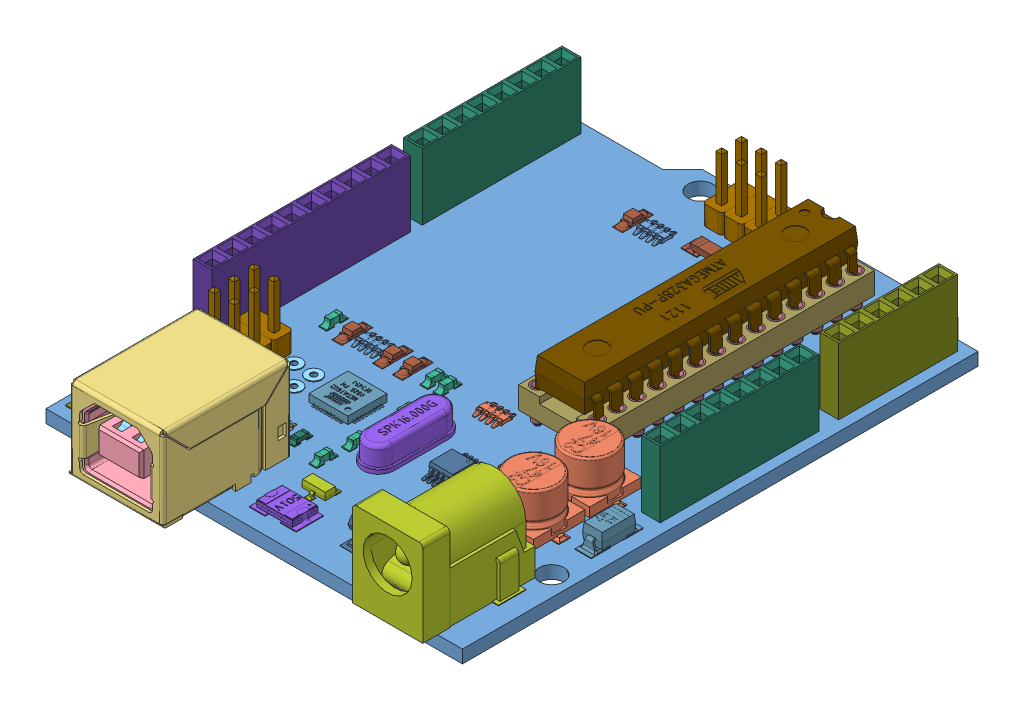
SolidWorks assembly arduino uno, configuration Default. Lengths in mm.
Overall size (53.34 15.25 74.97).
88 component instances, 35 part files, 136 mates.
Components (placement in the parent):
- unoboard blue-1: unoboard blue [Default] at origin size (53.34 1.65 68.58)
- 47uf CAP Dcase-1: 47uf CAP Dcase [Default] at (-9.4141 0 -18.4991) x (0 0 -1) z (1 0 0) size (6.6 5.81 8)
- USB type b-1: USB type b [Default] at (-38.02 0.43 6.35) size (14.34 15.2 16.54)
  - USB SHELL-1: USB SHELL [Default] at origin size (14.34 15.2 16.54)
  - USB core-1: USB core [Default] at origin size (11.3 10.68 15.75)
  - usb top contact-1: usb top contact [Default] at (1.25 6.09 -0.38) size (1 9.67 13.76)
  - usb btm contact-1: usb btm contact [Default] at (1.25 4.41 -0.38) size (1 6.84 11.76)
  - usb btm contact-2: usb btm contact [Default] at (-1.25 4.41 -0.38) size (1 6.84 11.76)
  - usb top contact-2: usb top contact [Default] at (-1.25 6.09 -0.38) size (1 9.67 13.76)
- power jack-1: power jack [Default] at (-7.675 0 1.905) size (11.2 15.2 15.9)
- 47uf CAP Dcase-2: 47uf CAP Dcase [Default] at (-9.4141 0 -25.7132) x (0 0 -1) z (1 0 0) size (6.6 5.81 8)
- crystal-1: crystal [Default] at (-26.162 0 -18.923) x (1 0 0) z (0 0 -1) size (4 5 11)
- 2pin_header__02-1: 2pin_header__02 [Default] at (-46.23 0 -15.75) size (5 11.75 2.54)
- nano - reg-1: nano - reg [Default] at (-17.399 0 -7.747) size (6.5 1.69 8.3)
- led-1: led [Default] at (-34.29 0 -27.94) x (0 0 1) z (-1 0 0) size (4 0.86 1.35)
- 2pin_header__02-2: 2pin_header__02 [Default] at (-30.43 0 -64.91) x (0 0 1) z (-1 0 0) size (5 11.75 2.54)
- dip28-1: dip28 [Default] at (-16.383 1.5 -46.355) x (0 0 -1) z (1 0 0) size (35.48 7.37 10.1)
  - dip28-1: dip28 [Default] at origin size (35.48 2.8 10.1)
  - dip socket pin-1: dip socket pin [Default] at (16.51 2.8 -3.81) size (1.7 7.37 1.7)
  - dip socket pin-2: dip socket pin [Default] at (16.51 2.8 3.81) size (1.7 7.37 1.7)
  - dip socket pin-3: dip socket pin [Default] at (13.97 2.8 -3.81) size (1.7 7.37 1.7)
  - dip socket pin-4: dip socket pin [Default] at (13.97 2.8 3.81) size (1.7 7.37 1.7)
  - dip socket pin-5: dip socket pin [Default] at (11.43 2.8 -3.81) size (1.7 7.37 1.7)
  - dip socket pin-6: dip socket pin [Default] at (11.43 2.8 3.81) size (1.7 7.37 1.7)
  - dip socket pin-7: dip socket pin [Default] at (8.89 2.8 -3.81) size (1.7 7.37 1.7)
  - dip socket pin-8: dip socket pin [Default] at (8.89 2.8 3.81) size (1.7 7.37 1.7)
  - dip socket pin-9: dip socket pin [Default] at (6.35 2.8 -3.81) size (1.7 7.37 1.7)
  - dip socket pin-10: dip socket pin [Default] at (6.35 2.8 3.81) size (1.7 7.37 1.7)
  - dip socket pin-11: dip socket pin [Default] at (3.81 2.8 -3.81) size (1.7 7.37 1.7)
  - dip socket pin-12: dip socket pin [Default] at (3.81 2.8 3.81) size (1.7 7.37 1.7)
  - dip socket pin-13: dip socket pin [Default] at (1.27 2.8 -3.81) size (1.7 7.37 1.7)
  - dip socket pin-14: dip socket pin [Default] at (1.27 2.8 3.81) size (1.7 7.37 1.7)
  - dip socket pin-15: dip socket pin [Default] at (-1.27 2.8 -3.81) size (1.7 7.37 1.7)
  - dip socket pin-16: dip socket pin [Default] at (-1.27 2.8 3.81) size (1.7 7.37 1.7)
  - dip socket pin-17: dip socket pin [Default] at (-3.81 2.8 -3.81) size (1.7 7.37 1.7)
  - dip socket pin-18: dip socket pin [Default] at (-3.81 2.8 3.81) size (1.7 7.37 1.7)
  - dip socket pin-19: dip socket pin [Default] at (-6.35 2.8 -3.81) size (1.7 7.37 1.7)
  - dip socket pin-20: dip socket pin [Default] at (-6.35 2.8 3.81) size (1.7 7.37 1.7)
  - dip socket pin-21: dip socket pin [Default] at (-8.89 2.8 -3.81) size (1.7 7.37 1.7)
  - dip socket pin-22: dip socket pin [Default] at (-8.89 2.8 3.81) size (1.7 7.37 1.7)
  - dip socket pin-23: dip socket pin [Default] at (-11.43 2.8 -3.81) size (1.7 7.37 1.7)
  - dip socket pin-24: dip socket pin [Default] at (-11.43 2.8 3.81) size (1.7 7.37 1.7)
  - dip socket pin-25: dip socket pin [Default] at (-13.97 2.8 -3.81) size (1.7 7.37 1.7)
  - dip socket pin-26: dip socket pin [Default] at (-13.97 2.8 3.81) size (1.7 7.37 1.7)
  - dip socket pin-27: dip socket pin [Default] at (-16.51 2.8 -3.81) size (1.7 7.37 1.7)
  - dip socket pin-28: dip socket pin [Default] at (-16.51 2.8 3.81) size (1.7 7.37 1.7)
- 2pin_header__02-3: 2pin_header__02 [Default] at (-27.89 0 -64.91) x (0 0 1) z (-1 0 0) size (5 11.75 2.54)
- 2pin_header__02-4: 2pin_header__02 [Default] at (-25.35 0 -64.91) x (0 0 1) z (-1 0 0) size (5 11.75 2.54)
- 2pin_header__02-5: 2pin_header__02 [Default] at (-46.23 0 -18.29) size (5 11.75 2.54)
- 2pin_header__02-6: 2pin_header__02 [Default] at (-46.23 0 -20.83) size (5 11.75 2.54)
- atmega16u2-1: atmega16u2 [Default] at (-34.671 0.06 -20) x (1 0 0) z (0 0 -1) size (5.5 1.01 5.5)
- led-2: led [Default] at (-36.83 0 -27.94) x (0 0 1) z (-1 0 0) size (4 0.86 1.35)
- led-3: led [Default] at (-42.037 0 -27.94) x (0 0 1) z (-1 0 0) size (4 0.86 1.35)
- led-4: led [Default] at (-36.576 0 -58.42) x (0 0 1) z (-1 0 0) size (4 0.86 1.35)
- 8 PORT HEADER-3: 8 PORT HEADER [Default] at (-50.8 0 -45.72) x (0 0 -1) z (1 0 0) size (20.32 10.51 2.41)
- 8 PORT HEADER-4: 8 PORT HEADER [Default] at (-2.54 0 -27.94) x (0 0 -1) z (1 0 0) size (20.32 10.51 2.41)
- 6 PORT HEADER-3: 6 PORT HEADER [Default] at (-2.54 0 -50.8) x (0 0 -1) z (1 0 0) size (15.24 10.51 2.41)
- 10 PORT HEADER-1: 10 PORT HEADER [Default] at (-50.8 0 -18.796) x (0 0 -1) z (1 0 0) size (25.4 10.51 2.41)
- ATMEL328P-1: ATMEL328P [Default] at (-16.383 4.3 -46.355) x (0 0 -1) z (1 0 0) size (35 7.27 7.87)
- 102 RESISTOR PACK-1: 102 RESISTOR PACK [Default] at (-33.782 0 -58.42) size (3.2 0.46 3)
- 102 RESISTOR PACK-2: 102 RESISTOR PACK [Default] at (-39.37 0 -27.94) size (3.2 0.46 3)
- 103 RESISTOR PACK-3: 103 RESISTOR PACK [Default] at (-23.876 0 -27.94) size (3.2 0.46 3)
- 220 RESISTOR PACK-1: 220 RESISTOR PACK [Default] at (-36.83 0 -12.827) size (3.2 0.46 3)
- 16mhz crystal - measured-1: 16mhz crystal - measured [Default] at (-24.892 0 -41.275) x (0 0 -1) z (1 0 0) size (3.4 0.8 2)
- PADS001-1: PADS001 [Default] at (-39.878 0.1 -18.288) x (-1 0 0) z (0 0 1) size (4.54 0.1 4.54)
- 603 cap on pad-1: 603 cap on pad [Default] at (-44.45 0 -27.94) x (0 0 -1) z (1 0 0) size (2.76 0.9 1.12)
- ssot3-1: ssot3 [Default] at (-26.5 0 -8.128) x (-1 0 0) z (0 0 -1) size (3 1.13 3.09)
- mf-msmf050-2-1: mf-msmf050-2 [Default] at (-26.5 0 -4.064) size (5.77 1.02 3.72)
- 603 cap on pad-2: 603 cap on pad [Default] at (-29.845 0 -27.94) x (0 0 -1) z (1 0 0) size (2.76 0.9 1.12)
- 603 cap on pad-3: 603 cap on pad [Default] at (-31.496 0 -27.94) x (0 0 -1) z (1 0 0) size (2.76 0.9 1.12)
- lmv358-1: lmv358 [Default] at (-15.24 0 -21.971) x (0 0 -1) z (1 0 0) size (3.7 1.4 2.9)
- 603 cap on pad-4: 603 cap on pad [Default] at (-15.24 0 -18.415) size (2.76 0.9 1.12)
- 603 cap on pad-5: 603 cap on pad [Default] at (-29.845 0 -12.065) x (0 0 1) z (-1 0 0) size (2.76 0.9 1.12)
- 603 cap on pad-6: 603 cap on pad [Default] at (-29.591 0 -22.352) x (0 0 1) z (-1 0 0) size (2.76 0.9 1.12)
- 603 cap on pad-7: 603 cap on pad [Default] at (-29.591 0 -16.002) x (0 0 1) z (-1 0 0) size (2.76 0.9 1.12)
- 603 cap on pad-8: 603 cap on pad [Default] at (-41.91 0 -12.7) x (0 0 1) z (-1 0 0) size (2.76 0.9 1.12)
- lp2985dgkr-1: lp2985dgkr [Default] at (-20.32 0 -19.05) x (0 0 -1) z (1 0 0) size (5.85 1.1 3)
- cd1206 diode-1: cd1206 diode [Default] at (-27.94 0 -59.436) x (0 0 -1) z (1 0 0) size (2.07 0.96 5)
- cd1206 diode-2: cd1206 diode [Default] at (-46.228 0 -13.081) x (0 0 1) z (-1 0 0) size (2.07 0.96 5)
- 603 resistor-1: 603 resistor [Default] at (-29.591 0 -19.05) x (0 0 1) z (-1 0 0) size (2.36 0.61 1.03)
- blm21-1: blm21 [Default] at (-45.085 0 -7.62) x (0 0 -1) z (1 0 0) size (2.76 0.95 1.32)
- m7 diode-1: m7 diode [Default] at (-2.794 0 -21.59) x (0 0 -1) z (1 0 0) size (6.66 2.35 2.5)
- MLC0603-1: MLC0603 [Default] at (-33.655 0 -12.827) x (0 0 -1) z (1 0 0) size (2.36 0.6 1.03)
- MLC0603-2: MLC0603 [Default] at (-39.37 0 -12.827) x (0 0 -1) z (1 0 0) size (2.36 0.6 1.03)
- RESET BUTTON-1: RESET BUTTON [Default] at (-49.403 0 -6.35) size (6.2 3.1 9.6)
  - RESET CORE-1: RESET CORE [Default] at (0 0.1 0) x (-1 0 0) z (0 0 -1) size (6.2 3.1 9.6)
  - RESET-1: RESET [Default] at (0 0.1 0) x (0 0 1) z (-1 0 0) size (7.3 2 6.2)
- 603 cap on pad-9: 603 cap on pad [Default] at (-15.24 0 -25.625) size (2.76 0.9 1.12)
Mates (geometry in assembly coordinates):
- Distance1: distance = 1.905 mm aligned: plane of power jack-1 through (-7.675 0 1.905) normal (0 0 1); plane of unoboard blue-1 through (0 0 0) normal (0 0 1)
- Coincident2: coincident aligned: plane of unoboard blue-1 through (0 0 0) normal (0 1 0); plane of power jack-1 through (-7.675 0 1.905) normal (0 1 0)
- Coincident3: coincident anti-aligned: plane of unoboard blue-1 through (0 0 0) normal (0 1 0); plane of USB type b-1/USB core-1 through (-38.02 0 6.35) normal (0 -1 0)
- Distance2: distance = 6.35 mm aligned: plane of USB type b-1/USB SHELL-1 through (-38.02 0.43 6.35) normal (0 0 1); plane of unoboard blue-1 through (0 0 0) normal (0 0 1)
- Coincident5: coincident aligned: plane of unoboard blue-1 through (0 0 0) normal (0 1 0); plane of 47uf CAP Dcase-1
- Parallel1: parallel anti-aligned: plane of unoboard blue-1 through (0 0 0) normal (0 0 1); plane of 47uf CAP Dcase-1 through (-9.4141 0 -18.4991) normal (0 0 -1)
- Coincident7: coincident aligned: plane of 47uf CAP Dcase-1 through (-6.1141 1.5 -15.1991) normal (1 0 0); plane of 47uf CAP Dcase-2 through (-6.1141 1.5 -22.4132) normal (1 0 0)
- Coincident8: coincident anti-aligned: plane of unoboard blue-1 through (0 0 0) normal (0 1 0); plane of 47uf CAP Dcase-2 through (-8.1891 0 -25.7132) normal (0 -1 0)
- Distance3: distance = 3.175 mm aligned: plane of power jack-1 through (-3.175 10.5 -1.595) normal (1 0 0); plane of unoboard blue-1 through (0 -1.65 0) normal (1 0 0)
- Distance4: distance = 32 mm aligned: plane of USB type b-1/USB SHELL-1 through (-32 0.43 6.35) normal (1 0 0); plane of unoboard blue-1 through (0 -1.65 0) normal (1 0 0)
- Coincident11: coincident anti-aligned: plane of unoboard blue-1 through (0 0 0) normal (0 1 0); plane of crystal-1 through (-26.162 0 -22.423) normal (0 -1 0)
- Concentric1: concentric aligned: cylinder of unoboard blue-1 through (-26.162 -10 -16.383) axis (0 1 0) radius 0.5; cylinder of crystal-1 through (-26.162 -2 -16.383) axis (0 1 0) radius 0.4
- Concentric2: concentric aligned: cylinder of unoboard blue-1 through (-26.162 -10 -21.463) axis (0 1 0) radius 0.5; cylinder of crystal-1 through (-26.162 -2 -21.463) axis (0 1 0) radius 0.4
- Coincident12: coincident anti-aligned: plane of unoboard blue-1 through (0 0 0) normal (0 1 0); plane of 2pin_header__02-1 through (-44.23 0 -14.98) normal (0 -1 0)
- Distance5: distance = 15.75 mm aligned: plane of 2pin_header__02-1 through (-46.23 0 -15.75) normal (0 0 1); plane of assembly through (0 0 0) normal (0 0 1)
- Distance6: distance = 46.23 mm aligned: plane of 2pin_header__02-1 through (-46.23 0 -15.75) normal (1 0 0); plane of assembly through (0 0 0) normal (1 0 0)
- Coincident15: coincident anti-aligned: plane of unoboard blue-1 through (0 0 0) normal (0 1 0); plane of 2pin_header__02-2 through (-31.2 0 -62.91) normal (0 -1 0)
- Distance7: distance = 64.91 mm aligned: plane of 2pin_header__02-2 through (-30.43 0 -64.91) normal (0 0 1); plane of assembly through (0 0 0) normal (0 0 1)
- Distance8: distance = 30.43 mm anti-aligned: plane of 2pin_header__02-2 through (-30.43 0 -64.91) normal (-1 0 0); plane of assembly through (0 0 0) normal (1 0 0)
- Coincident19: coincident anti-aligned: plane of unoboard blue-1 through (0 0 0) normal (0 1 0); plane of nano - reg-1 through (-17.399 0 -7.747) normal (0 -1 0)
- Concentric3: concentric aligned: cylinder of unoboard blue-1 through (-20.193 -10 -62.865) axis (0 1 0) radius 0.4; cylinder of dip28-1/dip socket pin-1 through (-20.193 33.2926 -62.865) axis (0 1 0) radius 0.25
- Concentric4: concentric aligned: cylinder of unoboard blue-1 through (-12.573 -10 -29.845) axis (0 1 0) radius 0.4; cylinder of dip28-1/dip socket pin-28 through (-12.573 33.2926 -29.845) axis (0 1 0) radius 0.25
- Distance9: distance = 1.5 mm anti-aligned: plane of dip28-1/dip28-1 through (-11.333 1.5 -64.095) normal (0 -1 0); plane of unoboard blue-1 through (0 0 0) normal (0 1 0)
- Coincident21: coincident anti-aligned: plane of unoboard blue-1 through (0 0 0) normal (0 1 0); plane of atmega16u2-1 through (-34.671 0 -20) normal (0 -1 0)
- Distance10: distance = 20 mm anti-aligned: plane of atmega16u2-1 through (-34.671 0.06 -20) normal (0 0 -1); plane of unoboard blue-1 through (0 0 0) normal (0 0 1)
- Distance11: distance = 34.671 mm aligned: plane of atmega16u2-1; plane of unoboard blue-1 through (0 0 0) normal (1 0 0)
- Coincident25: coincident anti-aligned: plane of unoboard blue-1 through (0 0 0) normal (0 1 0); plane of led-1 through (-34.29 0 -28.94) normal (0 -1 0)
- Distance12: distance = 34.29 mm anti-aligned: plane of led-1 through (-34.29 0 -27.94) normal (-1 0 0); plane of unoboard blue-1 through (0 0 0) normal (1 0 0)
- Distance13: distance = 27.94 mm aligned: plane of led-1 through (-34.29 0 -27.94) normal (0 0 1); plane of unoboard blue-1 through (0 0 0) normal (0 0 1)
- Coincident28: coincident aligned: plane of led-2 through (-36.83 0 -28.94) normal (0 -1 0); plane of led-3 through (-42.037 0 -28.94) normal (0 -1 0)
- Coincident29: coincident aligned: plane of led-1 through (-34.29 0 -27.94) normal (0 0 1); plane of led-2 through (-36.83 0 -27.94) normal (0 0 1)
- Coincident30: coincident aligned: plane of led-1 through (-34.29 0 -27.94) normal (0 0 1); plane of led-3 through (-42.037 0 -27.94) normal (0 0 1)
- Distance14: distance = 2.54 mm aligned: plane of led-2 through (-36.83 0 -27.94) normal (-1 0 0); plane of led-1 through (-34.29 0 -27.94) normal (-1 0 0)
- Coincident32: coincident anti-aligned: plane of unoboard blue-1 through (0 0 0) normal (0 1 0); plane of led-2 through (-36.83 0 -28.94) normal (0 -1 0)
- Distance15: distance = 42.037 mm anti-aligned: plane of led-3 through (-42.037 0 -27.94) normal (-1 0 0); plane of unoboard blue-1 through (0 0 0) normal (1 0 0)
- Coincident34: coincident anti-aligned: plane of unoboard blue-1 through (0 0 0) normal (0 1 0); plane of led-4 through (-36.576 0 -59.42) normal (0 -1 0)
- Distance16: distance = 36.576 mm anti-aligned: plane of led-4 through (-36.576 0 -58.42) normal (-1 0 0); plane of unoboard blue-1 through (0 0 0) normal (1 0 0)
- Distance17: distance = 58.42 mm aligned: plane of led-4 through (-36.576 0 -58.42) normal (0 0 1); plane of unoboard blue-1 through (0 0 0) normal (0 0 1)
- Coincident37: coincident aligned: plane of unoboard blue-1 through (0 0 0) normal (0 1 0); plane of 8 PORT HEADER-4
- Coincident38: coincident aligned: plane of unoboard blue-1 through (0 0 0) normal (0 1 0); plane of 8 PORT HEADER-3
- Parallel2: parallel aligned: plane of unoboard blue-1 through (0 0 0) normal (1 0 0); plane of 8 PORT HEADER-4 through (-2.54 0 -27.94) normal (1 0 0)
- Parallel3: parallel aligned: plane of unoboard blue-1 through (0 0 0) normal (1 0 0); plane of 8 PORT HEADER-3 through (-50.8 0 -45.72) normal (1 0 0)
- Concentric5: concentric aligned: cylinder of unoboard blue-1 through (-2.54 -1.65 -27.94) axis (0 1 0) radius 0.4; line of 8 PORT HEADER-4 through (-2.54 -2.5255 -27.94) axis (0 1 0)
- Concentric6: concentric aligned: cylinder of unoboard blue-1 through (-50.8 -1.65 -45.72) axis (0 1 0) radius 0.4; line of 8 PORT HEADER-3 through (-50.8 -2.5255 -45.72) axis (0 1 0)
- Coincident43: coincident aligned: plane of unoboard blue-1 through (0 0 0) normal (0 1 0); plane of 10 PORT HEADER-1
- Coincident44: coincident aligned: plane of unoboard blue-1 through (0 0 0) normal (0 1 0); plane of 6 PORT HEADER-3
- Parallel4: parallel aligned: plane of unoboard blue-1 through (0 0 0) normal (1 0 0); plane of 6 PORT HEADER-3 through (-2.54 0 -50.8) normal (1 0 0)
- Parallel5: parallel aligned: plane of unoboard blue-1 through (0 0 0) normal (1 0 0); plane of 10 PORT HEADER-1 through (-50.8 0 -18.796) normal (1 0 0)
- Concentric7: concentric aligned: cylinder of unoboard blue-1 through (-50.8 -1.65 -18.796) axis (0 1 0) radius 0.4; line of 10 PORT HEADER-1 through (-50.8 -2.5255 -18.796) axis (0 1 0)
- Concentric9: concentric aligned: cylinder of unoboard blue-1 through (-2.54 -1.65 -50.8) axis (0 1 0) radius 0.4; line of 6 PORT HEADER-3 through (-2.54 -2.5255 -50.8) axis (0 1 0)
- Coincident50: coincident aligned: plane of dip28-1/dip28-1 through (-16.383 1.5 -46.355) normal (0 0 -1); plane of ATMEL328P-1 through (-16.383 4.3 -46.355) normal (0 0 -1)
- Coincident51: coincident aligned: plane of dip28-1/dip28-1 through (-16.383 1.5 -46.355) normal (1 0 0); plane of ATMEL328P-1 through (-16.383 4.3 -46.355) normal (1 0 0)
- Coincident52: coincident aligned: plane of dip28-1/dip28-1 through (-11.333 4.3 -64.095) normal (0 1 0); plane of ATMEL328P-1
- Distance18: distance = 7.747 mm: plane of nano - reg-1 through (-17.399 0 -7.747) normal (0 0 1); line of unoboard blue-1 through (-53.34 0 0) axis (1 0 0)
- Distance19: distance = 17.399 mm aligned: plane of nano - reg-1 through (-17.399 0 -7.747) normal (1 0 0); plane of unoboard blue-1 through (0 0 0) normal (1 0 0)
- Coincident55: coincident anti-aligned: plane of unoboard blue-1 through (0 0 0) normal (0 1 0); plane of 102 RESISTOR PACK-1 through (-33.982 0 -59.12) normal (0 -1 0)
- Distance20: distance = 33.782 mm aligned: plane of 102 RESISTOR PACK-1 through (-33.782 0 -58.42) normal (1 0 0); plane of unoboard blue-1 through (0 0 0) normal (1 0 0)
- Distance21: distance = 58.42 mm aligned: plane of 102 RESISTOR PACK-1 through (-33.782 0 -58.42) normal (0 0 1); plane of unoboard blue-1 through (0 0 0) normal (0 0 1)
- Coincident58: coincident aligned: plane of 102 RESISTOR PACK-2 through (-39.37 0 -27.94) normal (0 1 0); plane of 103 RESISTOR PACK-3 through (-23.876 0 -27.94) normal (0 1 0)
- Coincident59: coincident aligned: plane of unoboard blue-1 through (0 0 0) normal (0 1 0); plane of 103 RESISTOR PACK-3 through (-23.876 0 -27.94) normal (0 1 0)
- Coincident60: coincident aligned: plane of 102 RESISTOR PACK-2 through (-39.37 0 -27.94) normal (0 0 1); plane of 103 RESISTOR PACK-3 through (-23.876 0 -27.94) normal (0 0 1)
- Distance22: distance = 23.876 mm aligned: plane of 103 RESISTOR PACK-3 through (-23.876 0 -27.94) normal (1 0 0); plane of unoboard blue-1 through (0 0 0) normal (1 0 0)
- Distance23: distance = 39.37 mm aligned: plane of 102 RESISTOR PACK-2 through (-39.37 0 -27.94) normal (1 0 0); plane of unoboard blue-1 through (0 0 0) normal (1 0 0)
- Distance24: distance = 27.94 mm aligned: plane of 102 RESISTOR PACK-2 through (-39.37 0 -27.94) normal (0 0 1); plane of unoboard blue-1 through (0 0 0) normal (0 0 1)
- Distance25: distance = 12.827 mm aligned: plane of 220 RESISTOR PACK-1 through (-36.83 0 -12.827) normal (0 0 1); plane of unoboard blue-1 through (0 0 0) normal (0 0 1)
- Distance26: distance = 36.83 mm aligned: plane of 220 RESISTOR PACK-1 through (-36.83 0 -12.827) normal (1 0 0); plane of unoboard blue-1 through (0 0 0) normal (1 0 0)
- Coincident66: coincident aligned: plane of unoboard blue-1 through (0 0 0) normal (0 1 0); plane of 220 RESISTOR PACK-1 through (-36.83 0 -12.827) normal (0 1 0)
- Coincident67: coincident anti-aligned: plane of unoboard blue-1 through (0 0 0) normal (0 1 0); plane of 16mhz crystal - measured-1 through (-24.892 0 -41.275) normal (0 -1 0)
- Distance27: distance = 41.275 mm anti-aligned: plane of 16mhz crystal - measured-1 through (-24.892 0 -41.275) normal (0 0 -1); plane of unoboard blue-1 through (0 0 0) normal (0 0 1)
- Distance28: distance = 24.892 mm aligned: plane of 16mhz crystal - measured-1 through (-24.892 0 -41.275) normal (1 0 0); plane of unoboard blue-1 through (0 0 0) normal (1 0 0)
- Coincident70: coincident anti-aligned: plane of unoboard blue-1 through (0 0 0) normal (0 1 0); plane of PADS001-1 through (-42.418 0 -18.288) normal (0 -1 0)
- Distance29: distance = 18.288 mm aligned: plane of PADS001-1 through (-39.878 0.1 -18.288) normal (0 0 1); plane of unoboard blue-1 through (0 0 0) normal (0 0 1)
- Distance30: distance = 39.878 mm anti-aligned: plane of PADS001-1; plane of unoboard blue-1 through (0 0 0) normal (1 0 0)
- Distance31: distance = 4.064 mm aligned: plane of mf-msmf050-2-1 through (-26.5 0 -4.064) normal (0 0 1); plane of unoboard blue-1 through (0 0 0) normal (0 0 1)
- Distance32: distance = 26.5 mm aligned: plane of mf-msmf050-2-1 through (-26.5 0 -4.064) normal (1 0 0); plane of unoboard blue-1 through (0 0 0) normal (1 0 0)
- Coincident72: coincident aligned: plane of unoboard blue-1 through (0 0 0) normal (0 1 0); plane of mf-msmf050-2-1 through (-26.5 0 -4.064) normal (0 1 0)
- Distance33: distance = 8.128 mm anti-aligned: plane of unoboard blue-1 through (0 0 0) normal (0 0 1); plane of ssot3-1 through (-26.5 0 -8.128) normal (0 0 -1)
- Coincident74: coincident anti-aligned: plane of ssot3-1 through (-26.5 0 -8.128) normal (-1 0 0); plane of mf-msmf050-2-1 through (-26.5 0 -4.064) normal (1 0 0)
- Coincident75: coincident aligned: plane of unoboard blue-1 through (0 0 0) normal (0 1 0); plane of ssot3-1
- Coincident76: coincident anti-aligned: plane of led-1 through (-34.29 0 -27.94) normal (0 0 1); plane of 603 cap on pad-1 through (-44.45 0 -27.94) normal (0 0 -1)
- Coincident77: coincident aligned: plane of unoboard blue-1 through (0 0 0) normal (0 1 0); plane of 603 cap on pad-1
- Distance34: distance = 44.45 mm aligned: plane of 603 cap on pad-1 through (-44.45 0 -27.94) normal (1 0 0); plane of unoboard blue-1 through (0 0 0) normal (1 0 0)
- Coincident79: coincident aligned: plane of 603 cap on pad-2; plane of 603 cap on pad-3
- Coincident80: coincident aligned: plane of 603 cap on pad-2 through (-29.845 0 -27.94) normal (0 0 -1); plane of 603 cap on pad-3 through (-31.496 0 -27.94) normal (0 0 -1)
- Coincident81: coincident aligned: plane of unoboard blue-1 through (0 0 0) normal (0 1 0); plane of 603 cap on pad-2
- Coincident82: coincident aligned: plane of 603 cap on pad-1 through (-44.45 0 -27.94) normal (0 0 -1); plane of 603 cap on pad-2 through (-29.845 0 -27.94) normal (0 0 -1)
- Distance36: distance = 29.845 mm aligned: plane of 603 cap on pad-2 through (-29.845 0 -27.94) normal (1 0 0); plane of unoboard blue-1 through (0 0 0) normal (1 0 0)
- Distance37: distance = 31.496 mm aligned: plane of 603 cap on pad-3 through (-31.496 0 -27.94) normal (1 0 0); plane of unoboard blue-1 through (0 0 0) normal (1 0 0)
- Distance38: distance = 15.24 mm aligned: plane of unoboard blue-1 through (0 0 0) normal (1 0 0); plane of lmv358-1 through (-15.24 0 -21.971) normal (1 0 0)
- Distance39: distance = 21.971 mm anti-aligned: plane of lmv358-1 through (-15.24 0 -21.971) normal (0 0 -1); plane of unoboard blue-1 through (0 0 0) normal (0 0 1)
- Coincident88: coincident aligned: plane of unoboard blue-1 through (0 0 0) normal (0 1 0); plane of lmv358-1
- Distance40: distance = 18.415 mm aligned: plane of 603 cap on pad-4 through (-15.24 0 -18.415) normal (0 0 1); plane of unoboard blue-1 through (0 0 0) normal (0 0 1)
- Distance41: distance = 15.24 mm aligned: plane of 603 cap on pad-4 through (-15.24 0 -18.415) normal (1 0 0); plane of unoboard blue-1 through (0 0 0) normal (1 0 0)
- Coincident91: coincident aligned: plane of unoboard blue-1 through (0 0 0) normal (0 1 0); plane of 603 cap on pad-4 through (-15.24 0 -18.415) normal (0 1 0)
- Coincident92: coincident aligned: plane of unoboard blue-1 through (0 0 0) normal (0 1 0); plane of 603 cap on pad-7
- Coincident93: coincident aligned: plane of unoboard blue-1 through (0 0 0) normal (0 1 0); plane of 603 cap on pad-6
- Coincident94: coincident aligned: plane of 603 cap on pad-5; plane of unoboard blue-1 through (0 0 0) normal (0 1 0)
- Coincident95: coincident aligned: plane of 603 cap on pad-8; plane of unoboard blue-1 through (0 0 0) normal (0 1 0)
- Coincident96: coincident aligned: plane of 603 cap on pad-7 through (-29.591 0 -16.002) normal (-1 0 0); plane of 603 cap on pad-6 through (-29.591 0 -22.352) normal (-1 0 0)
- Distance42: distance = 29.591 mm anti-aligned: plane of 603 cap on pad-7 through (-29.591 0 -16.002) normal (-1 0 0); plane of unoboard blue-1 through (0 0 0) normal (1 0 0)
- Distance43: distance = 22.352 mm: plane of 603 cap on pad-6 through (-29.591 0 -22.352) normal (0 0 1); line of unoboard blue-1 through (-53.34 0 0) axis (1 0 0)
- Distance44: distance = 16.002 mm aligned: plane of 603 cap on pad-7 through (-29.591 0 -16.002) normal (0 0 1); plane of unoboard blue-1 through (0 0 0) normal (0 0 1)
- Distance45: distance = 29.845 mm anti-aligned: plane of 603 cap on pad-5 through (-29.845 0 -12.065) normal (-1 0 0); plane of unoboard blue-1 through (0 0 0) normal (1 0 0)
- Distance46: distance = 12.065 mm aligned: plane of 603 cap on pad-5 through (-29.845 0 -12.065) normal (0 0 1); plane of unoboard blue-1 through (0 0 0) normal (0 0 1)
- Distance47: distance = 41.91 mm anti-aligned: plane of 603 cap on pad-8 through (-41.91 0 -12.7) normal (-1 0 0); plane of unoboard blue-1 through (0 0 0) normal (1 0 0)
- Distance48: distance = 12.7 mm aligned: plane of 603 cap on pad-8 through (-41.91 0 -12.7) normal (0 0 1); plane of unoboard blue-1 through (0 0 0) normal (0 0 1)
- Distance49: distance = 20.32 mm aligned: plane of lp2985dgkr-1 through (-20.32 0 -19.05) normal (1 0 0); plane of unoboard blue-1 through (0 0 0) normal (1 0 0)
- Distance50: distance = 19.05 mm anti-aligned: plane of lp2985dgkr-1 through (-20.32 0 -19.05) normal (0 0 -1); plane of unoboard blue-1 through (0 0 0) normal (0 0 1)
- Coincident99: coincident aligned: plane of unoboard blue-1 through (0 0 0) normal (0 1 0); plane of lp2985dgkr-1
- Distance51: distance = 27.94 mm aligned: plane of cd1206 diode-1 through (-27.94 0 -59.436) normal (1 0 0); plane of unoboard blue-1 through (0 0 0) normal (1 0 0)
- Distance52: distance = 59.436 mm anti-aligned: plane of cd1206 diode-1 through (-27.94 0 -59.436) normal (0 0 -1); plane of unoboard blue-1 through (0 0 0) normal (0 0 1)
- Coincident102: coincident aligned: plane of unoboard blue-1 through (0 0 0) normal (0 1 0); plane of cd1206 diode-1
- Distance53: distance = 46.228 mm anti-aligned: plane of cd1206 diode-2 through (-46.228 0 -13.081) normal (-1 0 0); plane of unoboard blue-1 through (0 0 0) normal (1 0 0)
- Distance54: distance = 13.081 mm aligned: plane of unoboard blue-1 through (0 0 0) normal (0 0 1); plane of cd1206 diode-2 through (-46.228 0 -13.081) normal (0 0 1)
- Coincident105: coincident aligned: plane of unoboard blue-1 through (0 0 0) normal (0 1 0); plane of cd1206 diode-2
- Distance55: distance = 29.591 mm anti-aligned: plane of 603 resistor-1 through (-29.591 0 -19.05) normal (-1 0 0); plane of unoboard blue-1 through (0 0 0) normal (1 0 0)
- Distance56: distance = 19.05 mm aligned: plane of 603 resistor-1 through (-29.591 0 -19.05) normal (0 0 1); plane of unoboard blue-1 through (0 0 0) normal (0 0 1)
- Coincident108: coincident aligned: plane of unoboard blue-1 through (0 0 0) normal (0 1 0); plane of 603 resistor-1
- Distance57: distance = 7.62 mm anti-aligned: plane of blm21-1 through (-45.085 0 -7.62) normal (0 0 -1); plane of unoboard blue-1 through (0 0 0) normal (0 0 1)
- Distance58: distance = 45.085 mm aligned: plane of blm21-1 through (-45.085 0 -7.62) normal (1 0 0); plane of unoboard blue-1 through (0 0 0) normal (1 0 0)
- Distance59: distance = 21.59 mm anti-aligned: plane of m7 diode-1 through (-2.794 0 -21.59) normal (0 0 -1); plane of unoboard blue-1 through (0 0 0) normal (0 0 1)
- Distance60: distance = 2.794 mm aligned: plane of m7 diode-1 through (-2.794 0 -21.59) normal (1 0 0); plane of unoboard blue-1 through (0 0 0) normal (1 0 0)
- Coincident113: coincident aligned: plane of unoboard blue-1 through (0 0 0) normal (0 1 0); plane of m7 diode-1
- Coincident114: coincident anti-aligned: plane of 220 RESISTOR PACK-1 through (-36.83 0 -12.827) normal (0 0 1); plane of MLC0603-1 through (-33.655 0 -12.827) normal (0 0 -1)
- Distance61: distance = 33.655 mm aligned: plane of MLC0603-1 through (-33.655 0 -12.827) normal (1 0 0); plane of unoboard blue-1 through (0 0 0) normal (1 0 0)
- Coincident115: coincident aligned: plane of unoboard blue-1 through (0 0 0) normal (0 1 0); plane of MLC0603-1
- Coincident116: coincident aligned: plane of unoboard blue-1 through (0 0 0) normal (0 1 0); plane of blm21-1
- Coincident117: coincident anti-aligned: plane of 220 RESISTOR PACK-1 through (-36.83 0 -12.827) normal (0 0 1); plane of MLC0603-2 through (-39.37 0 -12.827) normal (0 0 -1)
- Coincident118: coincident aligned: plane of unoboard blue-1 through (0 0 0) normal (0 1 0); plane of MLC0603-2
- Distance62: distance = 39.37 mm aligned: plane of MLC0603-2 through (-39.37 0 -12.827) normal (1 0 0); plane of unoboard blue-1 through (0 0 0) normal (1 0 0)
- Distance63: distance = 49.403 mm aligned: plane of RESET BUTTON-1 through (-49.403 0 -6.35) normal (1 0 0); plane of unoboard blue-1 through (0 0 0) normal (1 0 0)
- Distance64: distance = 6.35 mm aligned: plane of RESET BUTTON-1; plane of unoboard blue-1 through (0 0 0) normal (0 0 1)
- Coincident122: coincident aligned: plane of unoboard blue-1 through (0 0 0) normal (0 1 0); plane of RESET BUTTON-1 through (-49.403 0 -6.35) normal (0 1 0)
- Coincident124: coincident anti-aligned: plane of unoboard blue-1 through (0 0 0) normal (0 1 0); plane of 603 cap on pad-9 through (-15.24 0 -25.625) normal (0 -1 0)
- Distance65: distance = 7.21 mm aligned: plane of 603 cap on pad-9 through (-14.84 0.125 -25.245) normal (0 0 1); plane of 603 cap on pad-4 through (-14.84 0.125 -18.035) normal (0 0 1)
- Coincident126: coincident aligned: plane of 603 cap on pad-4 through (-14.44 0.875 -18.79) normal (1 0 0); plane of 603 cap on pad-9 through (-14.44 0.875 -26) normal (1 0 0)
